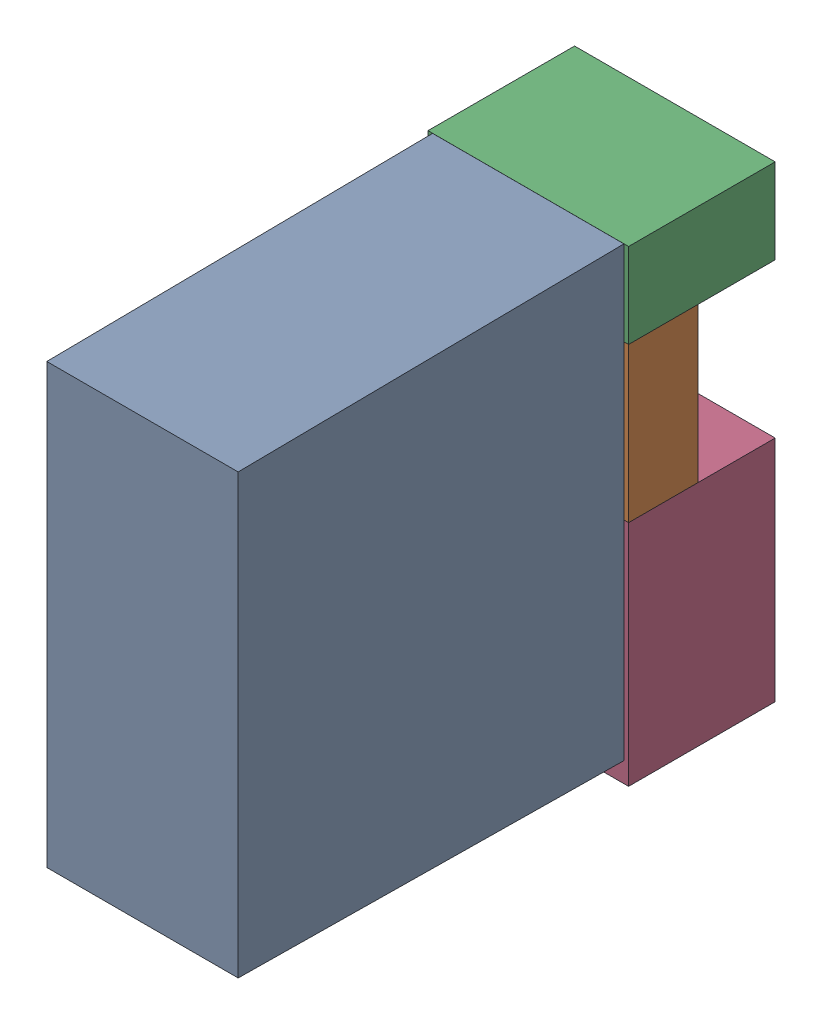
SolidWorks assembly K16, configuration Default. Lengths in mm.
Overall size (13 30.3 34.5).
7 component instances, 4 part files, 0 mates.
Components (placement in the parent):
- relais_40_61_8_006_0000-1: relais_40_61_8_006_0000 [Default] at (245.745 15.7216 9.5) x (0 1 0) z (1 0 0) size (29 30 12.4)
- 1151725064-1: 1151725064 [Default] at (245.745 34.225 5) size (13 10 4.5)
  - Extruded_3-1: Extruded_3 [Default] at origin size (13 10 4.5)
- 1151724928-1: 1151724928 [Default] at (245.745 41.975 0) size (13 5.5 9.5)
  - Extruded_2-1: Extruded_2 [Default] at origin size (13 5.5 9.5)
- 1151724792-1: 1151724792 [Default] at (245.745 21.825 0) size (13 14.8 9.5)
  - Extruded_4-1: Extruded_4 [Default] at origin size (13 14.8 9.5)
